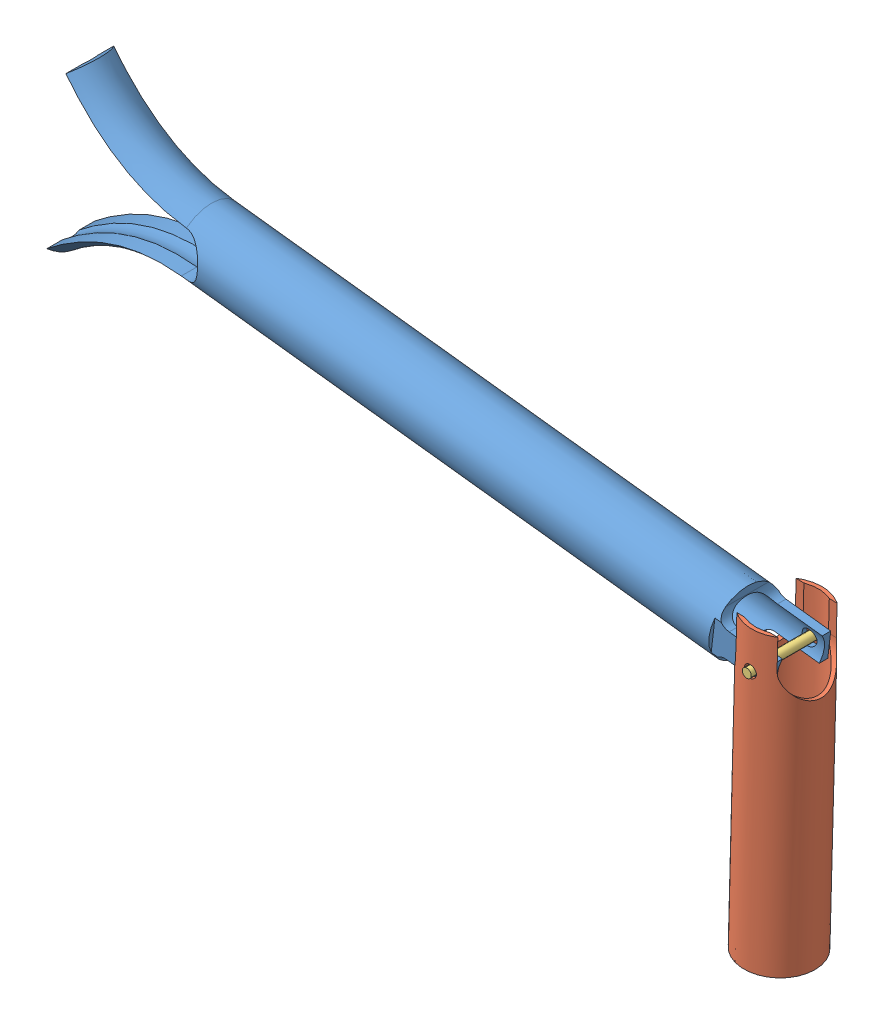
SolidWorks assembly pin joint assembly, configuration Default. Lengths in mm.
Overall size (26.59 24.58 19.36).
3 component instances, 3 part files, 5 mates.
Components (placement in the parent):
- tube-1: tube [Default] at (10.8718 0.4489 18.0506) x (0.116764 0.99316 0) z (0 0 1) size (6.18 24.36 2.18)
- stainless steel tube_pin joint-1: stainless steel tube_pin joint [Default] at (10.4086 1.7627 18.0506) x (-0.026615 -0.999646 0) z (0.999646 -0.026615 0) size (11.94 2.41 4.65)
- pin-1: pin [Default] at (10.3752 0.5073 19.3642) x (0 0 -1) z (0.825425 0.564511 0) size (2.54 0.3 0.3)
Mates (geometry in assembly coordinates):
- Concentric1: concentric anti-aligned: circle of tube-1; circle of stainless steel tube_pin joint-1
- Concentric2: concentric anti-aligned: circle of tube-1; circle of pin-1
- Coincident1: coincident anti-aligned: plane of tube-1 through (10.8718 0.4489 18.0506) normal (0 0 1); plane of stainless steel tube_pin joint-1
- Parallel1: parallel aligned: line of ? through (-35.1019 1.974 18.0506) axis (0.999646 -0.026615 0)
- Concentric3: concentric anti-aligned: circle of tube-1; circle of stainless steel tube_pin joint-1
